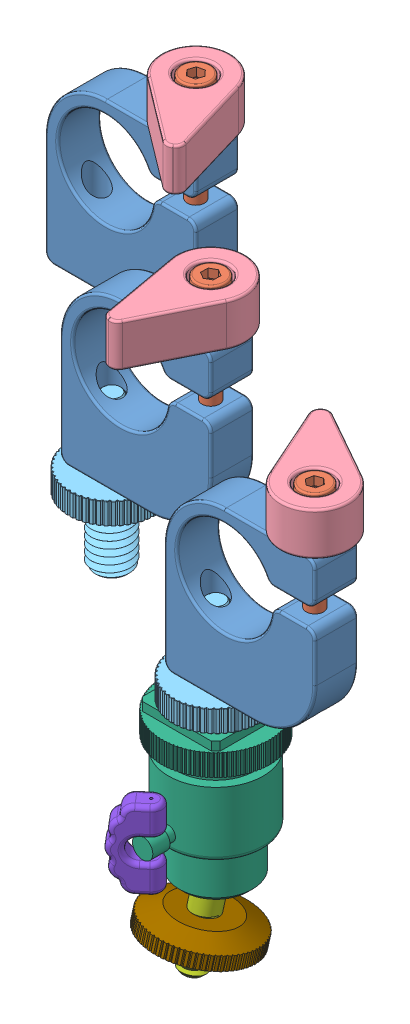
SolidWorks assembly one_adapter_for_22mm, configuration По умолчанию. Lengths in mm.
Overall size (137.32 110.38 101.27).
25 component instances, 10 part files, 14 mates.
Components (placement in the parent):
- 1-4_monitor_holder_on_pipe_22-1: 1-4_monitor_holder_on_pipe_22 [По умолчанию] at (-8.7684 7.0391 -4.27) size (35 39.2 10)
- flag_screw-1: flag_screw [По умолчанию] at (33.4323 8.9485 -46.2608) x (0.822035 0 -0.569437) z (0.569437 0 0.822035) size (16 29 29)
  - flag-1: flag [По умолчанию] at (-48.2962 13.0906 23.7085) size (16 10 29) (hidden)
  - socket head cap screw_din_1-1: socket head cap screw_din_1 [DIN 912 M4 x 25 --- 25N] at (-48.2962 23.0906 23.7085) x (0 -1 0) z (-0.387543 0 0.921852) size (29 7 7)
  - plain washer 6902 type abc_din-1: plain washer 6902 type abc_din [DIN 6902-A4.55] at (-48.2962 13.0906 23.7085) x (0 -1 0) z (-0.000413 0 1) size (1 10 10)
  - flag_drop-1: flag_drop [По умолчанию] at (-48.2962 13.0906 23.7085) x (1 0 0) z (0 1 0) size (16 29 10)
- adapter_1-4_3-8-1: adapter_1-4_3-8 [По умолчанию] at (26.3979 -23.1609 39.4369) x (1 0 0) z (0 1 0) size (20 20 36.58)
- 1-4_monitor_holder_on_pipe_22-2: 1-4_monitor_holder_on_pipe_22 [По умолчанию] at (33.3979 7.0391 34.4369) size (35 39.2 10)
- flag_screw-2: flag_screw [По умолчанию] at (100.5585 8.9485 22.7876) x (0.989975 0 0.141243) z (-0.141243 0 0.989975) size (16 29 29)
  - flag-1: flag [По умолчанию] at (-48.2962 13.0906 23.7085) size (16 10 29) (hidden)
  - socket head cap screw_din_1-1: socket head cap screw_din_1 [DIN 912 M4 x 25 --- 25N] at (-48.2962 23.0906 23.7085) x (0 -1 0) z (-0.387543 0 0.921852) size (29 7 7)
  - plain washer 6902 type abc_din-1: plain washer 6902 type abc_din [DIN 6902-A4.55] at (-48.2962 13.0906 23.7085) x (0 -1 0) z (-0.000413 0 1) size (1 10 10)
  - flag_drop-1: flag_drop [По умолчанию] at (-48.2962 13.0906 23.7085) x (1 0 0) z (0 1 0) size (16 29 10)
- flag_screw-3: flag_screw [По умолчанию] at (83.4599 8.9485 119.1438) x (-0.740014 0 0.672592) z (-0.672592 0 -0.740014) size (16 29 29)
  - flag-1: flag [По умолчанию] at (-48.2962 13.0906 23.7085) size (16 10 29) (hidden)
  - socket head cap screw_din_1-1: socket head cap screw_din_1 [DIN 912 M4 x 25 --- 25N] at (-48.2962 23.0906 23.7085) x (0 -1 0) z (-0.387543 0 0.921852) size (29 7 7)
  - plain washer 6902 type abc_din-1: plain washer 6902 type abc_din [DIN 6902-A4.55] at (-48.2962 13.0906 23.7085) x (0 -1 0) z (-0.000413 0 1) size (1 10 10)
  - flag_drop-1: flag_drop [По умолчанию] at (-48.2962 13.0906 23.7085) x (1 0 0) z (0 1 0) size (16 29 10)
- 1-4_monitor_holder_on_pipe_22-3: 1-4_monitor_holder_on_pipe_22 [По умолчанию] at (87.2536 7.0391 64.1156) size (35 39.2 10)
- adapter_1-4_3-8-2: adapter_1-4_3-8 [По умолчанию] at (80.2536 -23.1609 69.1156) x (1 0 0) z (0 1 0) size (20 20 36.58)
- arm_assembly-1: arm_assembly [По умолчанию] at (159.0656 8.9373 39.8971) x (1 0 0) z (0 -1 0) size (29.47 34.25 55.18)
  - base-1: base [По умолчанию] at (-78.812 29.2185 42.0982) size (25 29.5 35)
  - 1.4-1: 1.4 [По умолчанию] at (-78.812 29.2185 64.0452) x (0.997287 0.036081 0.064159) z (0.023037 -0.980828 0.193509) size (9 27.05 9)
  - thumb_screw-1: thumb_screw [По умолчанию] at (-78.812 44.2306 44.6037) x (0.643117 0.765768 0) z (0 0 1) size (5 10 18)
  - bulb_screw-1: bulb_screw [По умолчанию] at (-79.8524 32.0686 78.615) x (-0.317759 0.926003 -0.203831) z (0.069911 -0.191506 -0.978998) size (23 23 6)
Mates (geometry in assembly coordinates):
- Концентричный2: concentric aligned: cylinder of 1-4_monitor_holder_on_pipe_22-1 through (7.2316 21.0391 0.73) axis (0 1 0) radius 2.25; cylinder of flag_screw-1/socket head cap screw_din_1-1 through (7.2316 63.7891 0.73) axis (0 1 0) radius 2
- Совпадение1: coincident anti-aligned: plane of 1-4_monitor_holder_on_pipe_22-1 through (-8.7684 21.0391 5.73) normal (0 1 0); plane of flag_screw-1/plain washer 6902 type abc_din-1 through (7.2316 21.0391 0.73) normal (0 -1 0)
- Концентричный4: concentric aligned: cylinder of 1-4_monitor_holder_on_pipe_22-2 through (49.3979 21.0391 39.4369) axis (0 1 0) radius 2.25; cylinder of flag_screw-2/socket head cap screw_din_1-1 through (49.3979 63.7891 39.4369) axis (0 1 0) radius 2
- Совпадение2: coincident anti-aligned: plane of 1-4_monitor_holder_on_pipe_22-2 through (33.3979 21.0391 44.4369) normal (0 1 0); plane of flag_screw-2/plain washer 6902 type abc_din-1 through (49.3979 21.0391 39.4369) normal (0 -1 0)
- Концентричный5: concentric anti-aligned: circle of adapter_1-4_3-8-1; cylinder of 1-4_monitor_holder_on_pipe_22-2 through (26.3979 -18.1609 39.4369) axis (0 -1 0) radius 2.5527
- Совпадение3: coincident anti-aligned: plane of adapter_1-4_3-8-1 through (26.3979 -18.1609 39.4369) normal (0 1 0); plane of 1-4_monitor_holder_on_pipe_22-2 through (19.3979 -18.1609 44.4369) normal (0 -1 0)
- Концентричный6: concentric aligned: cylinder of flag_screw-3/socket head cap screw_din_1-1 through (103.2536 63.7891 69.1156) axis (0 1 0) radius 2; cylinder of 1-4_monitor_holder_on_pipe_22-3 through (103.2536 21.0391 69.1156) axis (0 1 0) radius 2.25
- Совпадение4: coincident anti-aligned: plane of flag_screw-3/plain washer 6902 type abc_din-1 through (103.2536 21.0391 69.1156) normal (0 -1 0); plane of 1-4_monitor_holder_on_pipe_22-3 through (87.2536 21.0391 74.1156) normal (0 1 0)
- Концентричный7: concentric anti-aligned: cylinder of 1-4_monitor_holder_on_pipe_22-3 through (80.2536 -18.1609 69.1156) axis (0 -1 0) radius 2.5527; circle of adapter_1-4_3-8-2
- Совпадение5: coincident anti-aligned: plane of 1-4_monitor_holder_on_pipe_22-3 through (73.2536 -18.1609 74.1156) normal (0 -1 0); plane of adapter_1-4_3-8-2 through (80.2536 -18.1609 69.1156) normal (0 1 0)
- Концентричный8: concentric aligned: circle of adapter_1-4_3-8-2; cylinder of arm_assembly-1/base-1 through (80.2536 -23.1609 69.1156) axis (0 1 0) radius 2.5527
- Совпадение7: coincident anti-aligned: plane of adapter_1-4_3-8-2 through (80.2536 -23.1609 69.1156) normal (0 -1 0); plane of arm_assembly-1/base-1 through (80.2536 -23.1609 69.1156) normal (0 1 0)
- Совпадение8: coincident aligned: plane of flag_screw-1/flag_drop-1 through (7.2316 32.0391 0.73) normal (0 1 0); plane of flag_screw-2/flag_drop-1 through (49.3979 32.0391 39.4369) normal (0 1 0)
- Совпадение9: coincident aligned: plane of flag_screw-2/flag_drop-1 through (49.3979 32.0391 39.4369) normal (0 1 0); plane of flag_screw-3/flag_drop-1 through (103.2536 32.0391 69.1156) normal (0 1 0)
